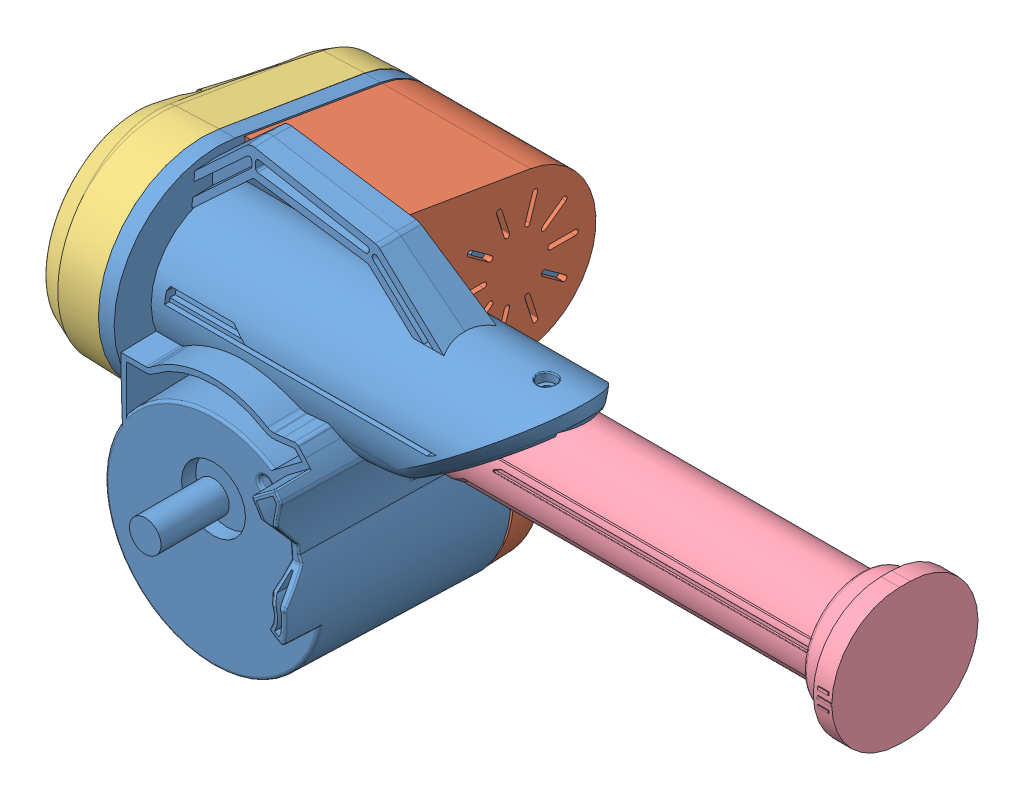
SolidWorks assembly Mirobot_Link3, configuration 默认. Lengths in mm.
Overall size (167.71 84.01 80.56).
4 component instances, 4 part files, 10 mates.
Components (placement in the parent):
- 10中关节-1: 10中关节 [默认] at (15.2267 9.3067 -18.44) x (0 -1 0) z (0 0 1) size (75.61 74.62 74.94)
- 11中关节盖-1: 11中关节盖 [默认] at (-0.0018 -43.4251 -31.355) x (1 0 0) z (0 0 -1) size (42.77 67.95 38.74)
- 16中关节后盖-1: 16中关节后盖 [默认] at (-20.6118 -17.635 -30.2843) x (0 -0.001809 0.999998) z (-1 0 0) size (76.1 71.71 60.93)
- 12中关节管-3: 12中关节管 [默认] at (80.5287 -4.4953 -18.44) x (0 -1 0) z (0 0 1) size (25.84 105.18 28.04)
Mates (geometry in assembly coordinates):
- 重合3: coincident anti-aligned: plane of 10中关节-1 through (-20.6118 20.3803 -18.44) normal (-1 0 0); plane of 16中关节后盖-1 through (-20.6118 20.3803 -18.44) normal (1 0 0)
- 平行3: parallel aligned: plane of 10中关节-1 through (-0.0018 0.3903 0) normal (0 0 1); plane of assembly through (0 0 0) normal (0 0 1)
- 重合5: coincident: plane of 10中关节-1 through (-0.0018 0.3903 0) normal (0 0 1)
- 同心9: concentric: cylinder of 10中关节-1 through (0 0 20) axis (0 0 -1) radius 3; point of assembly
- 平行4: parallel anti-aligned: plane of 10中关节-1 through (53.0871 29.5803 -22.64) normal (0 -1 0); plane of 12中关节管-3 through (28.0382 29.3803 -22.5631) normal (0 1 0)
- 同心10: concentric aligned: cylinder of 10中关节-1 through (-26.6218 20.3803 -18.44) axis (1 0 0) radius 12.715; cylinder of 12中关节管-3 through (48.0382 20.3803 -18.44) axis (1 0 0) radius 9
- 同心11: concentric anti-aligned: cylinder of 10中关节-1 through (45.0382 47.0452 -18.44) axis (0 -1 0) radius 1.7; cylinder of 12中关节管-3 through (45.0382 29.3803 -18.44) axis (0 1 0) radius 0.75
- 同心12: concentric aligned: cylinder of 10中关节-1 through (-10.6118 20.3803 -18.44) axis (-1 0 0) radius 19.75; cone of 16中关节后盖-1 through (-20.6118 20.3803 -18.44) axis (-1 0 0)
- 同心14: concentric aligned: circle of 10中关节-1; cylinder of 11中关节盖-1 through (13.4622 13.1095 -32.955) axis (0 0 -1) radius 1.65
- 重合13: coincident anti-aligned: plane of 10中关节-1 through (-21.5118 -8.8737 -35.816) normal (0 0 -1); plane of 11中关节盖-1 through (-21.5118 -8.8737 -35.816) normal (0 0 1)
